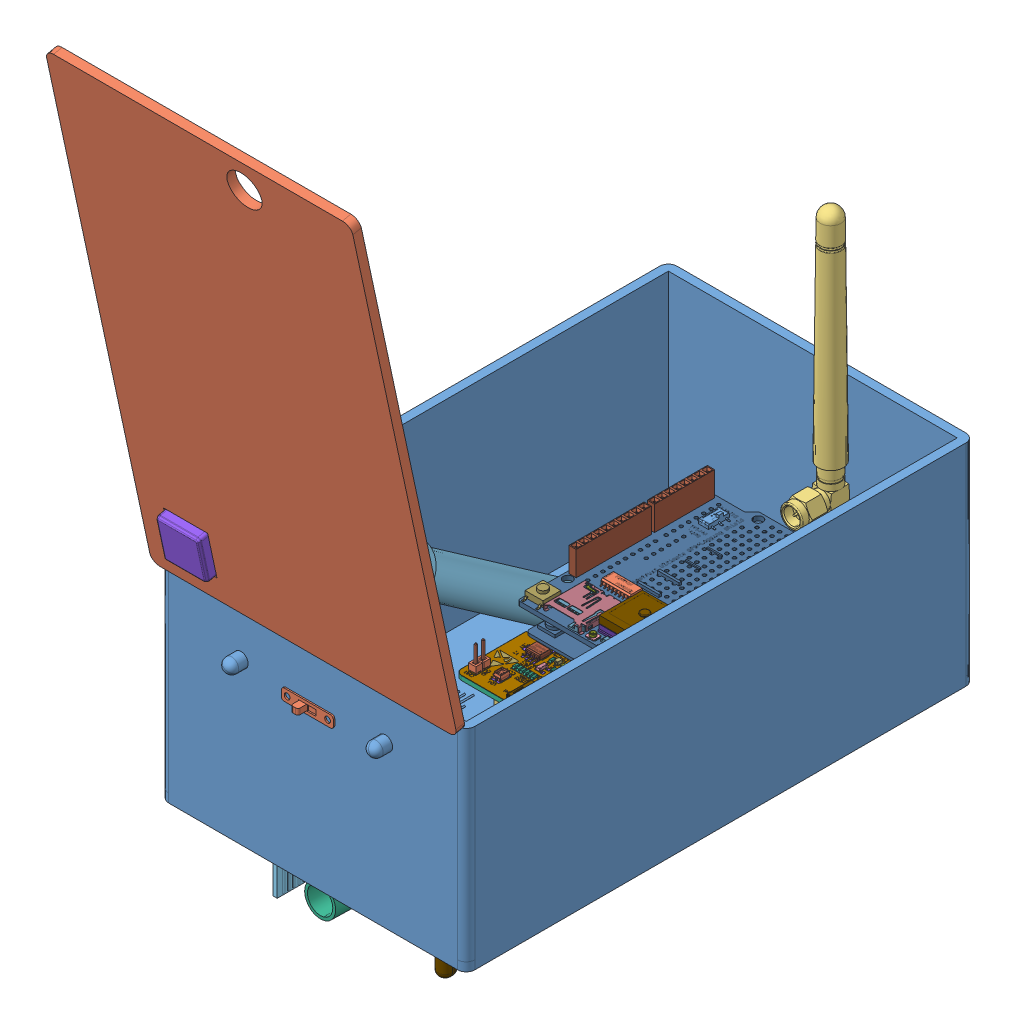
SolidWorks assembly box, configuration Défaut. Lengths in mm.
Overall size (1043.35 347.05 970.79).
170 component instances, 80 part files, 35 mates.
Components (placement in the parent):
- lower_part_box-1: lower_part_box [Défaut] at (-127.2122 -54.0126 451.3328) size (1043.35 316.3 970.79)
- upper_part_box-1: upper_part_box [Défaut] at (-127.2122 102.0269 557.8044) x (0 0.977722 0.209904) z (1 0 0) size (176 3 106)
- Batterie nel portabatterie-1: Batterie nel portabatterie [Default] at (-130.8735 -47.9133 432.4312) x (1 0 0) z (0 1 0) size (59.56 63.27 19.72)
  - User Library-R6_AA_UM3-1_5V_holder4AA-2: User Library-R6_AA_UM3-1_5V_holder4AA [4AA] at (18.4086 0.1871 -6.0993) size (59.56 61.47 15.11)
  - Batteria ricaricabile stilo-1: Batteria ricaricabile stilo [Default] at (-5.4514 -22.5579 1.9017) x (0 0 1) z (1 0 0) size (13.97 13.97 50.04)
  - Batteria ricaricabile stilo-3: Batteria ricaricabile stilo [Default] at (-5.4514 7.5731 1.9017) x (0 0 1) z (1 0 0) size (13.97 13.97 50.04)
  - Batteria ricaricabile stilo-4: Batteria ricaricabile stilo [Default] at (42.2686 -7.2677 1.9017) x (0 0.660431 0.750887) z (-1 0 0) size (13.97 13.97 50.04)
  - Batteria ricaricabile stilo-5: Batteria ricaricabile stilo [Default] at (42.2686 22.8633 1.9017) x (0 0.660431 0.750887) z (-1 0 0) size (13.97 13.97 50.04)
- ph_sonda v1.step-1: ph_sonda v1.step [Défaut] at (-166.4758 -79.6585 378.5757) x (0.97654 -0.176393 0.123512) z (0 0.573576 0.819152) size (16.6 16.6 161)
- NUCLEO-F411RE.STEP-1: NUCLEO-F411RE.STEP [Défaut] at (-121.1022 -38.1146 390.069) x (-1 0 0) z (0 1 0) size (70 83.97 20.27)
  - NUCLEO-F411RE_PCB_Varsay_lan.STEP-1: NUCLEO-F411RE_PCB_Varsay_lan.STEP [Défaut] at origin size (70 82.5 1.5)
  - NUCLEO-F411RE_PCB_HOLEs_Varsay_lan.STEP-1: NUCLEO-F411RE_PCB_HOLEs_Varsay_lan.STEP [Défaut] at origin size (65.28 79.87 1.57)
  - NUCLEO-F411RE_PCB_TOP_Pads_Varsay_lan.STEP-1: NUCLEO-F411RE_PCB_TOP_Pads_Varsay_lan.STEP [Défaut] at origin size (59.94 77.1 0.04)
  - NUCLEO-F411RE_PCB_TOP_Solder_Varsay_lan.STEP-1: NUCLEO-F411RE_PCB_TOP_Solder_Varsay_lan.STEP [Défaut] at origin size (69.8 82.3 0.05)
  - NUCLEO-F411RE_PCB_BOTTOM_Pads_Varsay_lan.STEP-1: NUCLEO-F411RE_PCB_BOTTOM_Pads_Varsay_lan.STEP [Défaut] at origin size (31.1 70.87 0.04)
  - NUCLEO-F411RE_PCB_BOTTOM_Solder_Varsay_lan.STEP-1: NUCLEO-F411RE_PCB_BOTTOM_Solder_Varsay_lan.STEP [Défaut] at origin size (69.8 82.3 0.04)
  - NUCLEO-F411RE_PCB_TOP_Overlay_Varsay_lan.STEP-1: NUCLEO-F411RE_PCB_TOP_Overlay_Varsay_lan.STEP [Défaut] at origin size (68.09 77.67 0)
  - NUCLEO-F411RE_PCB_TOP_Designators_Varsay_lan.STEP-1: NUCLEO-F411RE_PCB_TOP_Designators_Varsay_lan.STEP [Défaut] at origin size (66.29 79.64 0)
  - NUCLEO-F411RE_PCB_BOTTOM_Overlay_Varsay_lan.STEP-1: NUCLEO-F411RE_PCB_BOTTOM_Overlay_Varsay_lan.STEP [Défaut] at origin size (40.11 80.77 0)
  - SAMTEC_SSQ-106-01-G-S_for_NUCLEO_Varsay_lan.STEP-1: SAMTEC_SSQ-106-01-G-S_for_NUCLEO_Varsay_lan.STEP [Défaut] at (-33.02 8.89 0.785) x (0 1 0) z (1 0 0) size (15.75 11.15 2.41)
  - SAMTEC_SSQ-108-01-G-S_for_NUCLEO_Varsay_lan.STEP-1: SAMTEC_SSQ-108-01-G-S_for_NUCLEO_Varsay_lan.STEP [Défaut] at (-33.02 29.21 0.785) x (0 1 0) z (1 0 0) size (20.83 11.15 2.41)
  - SAMTEC_SSQ-108-01-G-S_for_NUCLEO_Varsay_lan.STEP-2: SAMTEC_SSQ-108-01-G-S_for_NUCLEO_Varsay_lan.STEP [Défaut] at (15.24 11.43 0.785) x (0 1 0) z (1 0 0) size (20.83 11.15 2.41)
  - SAMTEC_SSQ-110-01-G-S_for_NUCLEO_Varsay_lan.STEP-1: SAMTEC_SSQ-110-01-G-S_for_NUCLEO_Varsay_lan.STEP [Défaut] at (15.24 35.814 0.785) x (0 1 0) z (1 0 0) size (25.91 11.15 2.41)
  - MOLEX_0678038020_for_NUCLEO.STEP-1: MOLEX_0678038020_for_NUCLEO.STEP [Défaut] at (3.1721 75.2975 0.785) x (-1 0 0) z (0 1 0) size (9.9 4.95 9)
  - SAMTEC_TSW-119-07-T-D_for_NUCLEO_Varsay_lan.STEP-1: SAMTEC_TSW-119-07-T-D_for_NUCLEO_Varsay_lan.STEP [Défaut] at (-39.37 25.4 0.785) x (0 -1 0) z (-1 0 0) size (48.26 17.95 5.08)
  - SAMTEC_TSW-119-07-T-D_for_NUCLEO_Varsay_lan.STEP-2: SAMTEC_TSW-119-07-T-D_for_NUCLEO_Varsay_lan.STEP [Défaut] at (21.59 25.4 0.785) x (0 -1 0) z (-1 0 0) size (48.26 17.95 5.08)
  - SAMTEC_TSW-102-07-T-S_for_NUCLEO_Varsay_lan.STEP-1: SAMTEC_TSW-102-07-T-S_for_NUCLEO_Varsay_lan.STEP [Défaut] at (-40.64 74.93 0.785) x (0 1 0) z (1 0 0) size (5.08 10.92 2.54)
  - SAMTEC_TSW-102-07-T-S_for_NUCLEO_Varsay_lan.STEP-2: SAMTEC_TSW-102-07-T-S_for_NUCLEO_Varsay_lan.STEP [Défaut] at (-31.75 59.055 0.785) x (0 -1 0) z (-1 0 0) size (5.08 10.92 2.54)
  - SAMTEC_TSW-102-07-T-S_for_NUCLEO_Varsay_lan.STEP-3: SAMTEC_TSW-102-07-T-S_for_NUCLEO_Varsay_lan.STEP [Défaut] at (-9.525 77.47 0.785) x (1 0 0) z (0 -1 0) size (5.08 10.92 2.54)
  - SAMTEC_TSW-102-07-T-S_for_NUCLEO_Varsay_lan.STEP-4: SAMTEC_TSW-102-07-T-S_for_NUCLEO_Varsay_lan.STEP [Défaut] at (-9.525 38.735 0.785) x (1 0 0) z (0 -1 0) size (5.08 10.92 2.54)
  - SAMTEC_TSW-102-07-T-S_for_NUCLEO_Varsay_lan.STEP-5: SAMTEC_TSW-102-07-T-S_for_NUCLEO_Varsay_lan.STEP [Défaut] at (22.86 74.93 0.785) x (0 -1 0) z (-1 0 0) size (5.08 10.92 2.54)
  - SAMTEC_TSW-103-07-T-S_for_NUCLEO_Varsay_lan.STEP-1: SAMTEC_TSW-103-07-T-S_for_NUCLEO_Varsay_lan.STEP [Défaut] at (1.905 45.085 0.785) x (1 0 0) z (0 -1 0) size (7.62 10.92 2.54)
  - SAMTEC_TSW-104-07-T-S_for_NUCLEO_Varsay_lan.STEP-1: SAMTEC_TSW-104-07-T-S_for_NUCLEO_Varsay_lan.STEP [Défaut] at (-21.59 73.66 0.785) x (0 1 0) z (1 0 0) size (10.16 10.92 2.54)
  - SAMTEC_TSW-106-07-T-S_for_NUCLEO_Varsay_lan.STEP-1: SAMTEC_TSW-106-07-T-S_for_NUCLEO_Varsay_lan.STEP [Défaut] at (-35.56 64.77 0.785) x (0 1 0) z (1 0 0) size (15.24 10.92 2.54)
  - MOLEX_90059-0007.STEP-1: MOLEX_90059-0007.STEP [Défaut] at (-21.59 76.2 5.75) x (0 1 0) z (1 0 0) size (5.1 4.85 2.54)
  - MOLEX_90059-0007.STEP-2: MOLEX_90059-0007.STEP [Défaut] at (-21.59 71.12 5.75) x (0 -1 0) z (-1 0 0) size (5.1 4.85 2.54)
  - ST_STM32F411RET6_Varsay_lan.STEP-1: ST_STM32F411RET6_Varsay_lan.STEP [Défaut] at (-11.4265 21.5935 0.785) x (-1 0 0) z (0 0 -1) size (12 12 1.6)
  - ST_STM32F103CBT6_Varsay_lan.STEP-1: ST_STM32F103CBT6_Varsay_lan.STEP [Défaut] at (-8.89 64.77 0.785) x (1 0 0) z (0 -1 0) size (9 1.6 9)
  - ESWITCH_TL3301SPF160QGBLK_Varsay_lan.STEP-1: ESWITCH_TL3301SPF160QGBLK_Varsay_lan.STEP [Défaut] at (-0.635 50.8 0.785) x (0 -1 0) z (-1 0 0) size (6 10.7 10)
  - ESWITCH_TL3301SPF160QGBLU_Varsay_lan.STEP-1: ESWITCH_TL3301SPF160QGBLU_Varsay_lan.STEP [Défaut] at (-17.145 50.8 0.785) x (0 1 0) z (1 0 0) size (6 10.7 10)
  - ST_STS7PF30L_Varsay_lan.STEP-1: ST_STS7PF30L_Varsay_lan.STEP [Défaut] at (17.145 60.325 0.785) x (-1 0 0) z (0 1 0) size (4.9 1.75 6)
  - ABRACON_ABL-8.000MHZ-B2_Varsay_lan.STEP-1: ABRACON_ABL-8.000MHZ-B2_Varsay_lan.STEP [Défaut] at (-18.41 63.4908 0.785) x (0 -1 0) z (-1 0 0) size (11.5 5.57 5)
  - ST_LD1117S50TR_Varsay_lan.STEP-1: ST_LD1117S50TR_Varsay_lan.STEP [Défaut] at (-14.6685 43.18 0.785) x (0 -1 0) z (-1 0 0) size (6.5 1.9 7)
  - ST_LD39050PU33R_Varsay_lan.STEP-1: ST_LD39050PU33R_Varsay_lan.STEP [Défaut] at (1.905 40.64 0.785) x (0 1 0) z (1 0 0) size (3 1 3)
  - ST_LD3985M33R_Varsay_lan.STEP-1: ST_LD3985M33R_Varsay_lan.STEP [Défaut] at (7.62 63.5 0.785) x (1 0 0) z (0 -1 0) size (2.95 1.45 2.8)
  - KEMET_T491B106K025AT_Varsay_lan.STEP-1: KEMET_T491B106K025AT_Varsay_lan.STEP [Défaut] at (-22.86 41.275 0.785) x (0 -1 0) z (-1 0 0) size (2.8 1.9 3.5)
  - ST_STPS2L30A_Varsay_lan.STEP-1: ST_STPS2L30A_Varsay_lan.STEP [Défaut] at (-22.86 45.085 0.785) x (0 1 0) z (1 0 0) size (2.58 2.3 5.07)
  - KEMET_T491A106K006AT7280_Varsay_lan.STEP-1: KEMET_T491A106K006AT7280_Varsay_lan.STEP [Défaut] at (-8.255 43.053 0.785) x (1 0 0) z (0 -1 0) size (1.6 1.6 3.2)
  - ABRACON_ABS25-32.768KHZ-6-T_Varsay_lan.STEP-1: ABRACON_ABS25-32.768KHZ-6-T_Varsay_lan.STEP [Défaut] at (-23.495 6.35 0.785) x (1 0 0) z (0 -1 0) size (8 2.66 4)
  - LUMEX_SML-LX2835IGC-TR.STEP-1: LUMEX_SML-LX2835IGC-TR.STEP [Défaut] at (16.51 73.66 0.785) x (1 0 0) z (0 -1 0) size (2.7 1.8 3.5)
  - MOLEX_90059-0007.STEP-3: MOLEX_90059-0007.STEP [Défaut] at (3.175 45.085 5.75) x (-1 0 0) z (0 1 0) size (5.1 4.85 2.54)
  - ST_BAT60JFILM_Varsay_lan.STEP-1: ST_BAT60JFILM_Varsay_lan.STEP [Défaut] at (-31.115 71.12 0.785) x (0 -1 0) z (-1 0 0) size (1.28 1.17 2.5)
  - ST_BAT60JFILM_Varsay_lan.STEP-2: ST_BAT60JFILM_Varsay_lan.STEP [Défaut] at (7.62 69.85 0.785) x (0 -1 0) z (-1 0 0) size (1.28 1.17 2.5)
  - NXP_BC847B,215.STEP-1: NXP_BC847B,215.STEP [Défaut] at (12.065 64.135 0.785) x (0 -1 0) z (-1 0 0) size (2.9 1.1 2.43)
  - ST_BAT60JFILM_Varsay_lan.STEP-3: ST_BAT60JFILM_Varsay_lan.STEP [Défaut] at (10.795 59.69 0.785) x (1 0 0) z (0 -1 0) size (1.28 1.17 2.5)
  - YAGEO_CC0805KKX7R7BB225.STEP-1: YAGEO_CC0805KKX7R7BB225.STEP [Défaut] at (0.127 23.495 0.785) x (0 -1 0) z (-1 0 0) size (1.58 1.29 4.06)
  - YAGEO_RC0603JR-070RL.STEP-1: YAGEO_RC0603JR-070RL.STEP [Défaut] at (17.145 67.945 0.785) x (1 0 0) z (0 -1 0) size (0.8 0.55 2.16)
  - YAGEO_RC0603JR-070RL.STEP-2: YAGEO_RC0603JR-070RL.STEP [Défaut] at (15.875 67.945 0.785) x (1 0 0) z (0 -1 0) size (0.8 0.55 2.16)
  - YAGEO_RC0603JR-070RL.STEP-3: YAGEO_RC0603JR-070RL.STEP [Défaut] at (14.605 67.945 0.785) x (1 0 0) z (0 -1 0) size (0.8 0.55 2.16)
  - YAGEO_RC0603JR-070RL.STEP-4: YAGEO_RC0603JR-070RL.STEP [Défaut] at (13.335 67.945 0.785) x (1 0 0) z (0 -1 0) size (0.8 0.55 2.16)
  - YAGEO_RC0603JR-070RL.STEP-5: YAGEO_RC0603JR-070RL.STEP [Défaut] at (12.065 67.945 0.785) x (1 0 0) z (0 -1 0) size (0.8 0.55 2.16)
  - YAGEO_RC0603JR-070RL.STEP-6: YAGEO_RC0603JR-070RL.STEP [Défaut] at (10.795 67.945 0.785) x (1 0 0) z (0 -1 0) size (0.8 0.55 2.16)
  - YAGEO_RC0603JR-070RL.STEP-7: YAGEO_RC0603JR-070RL.STEP [Défaut] at (12.7 59.7535 0.785) x (1 0 0) z (0 -1 0) size (0.8 0.55 2.16)
  - YAGEO_RC0603JR-070RL.STEP-8: YAGEO_RC0603JR-070RL.STEP [Défaut] at (4.445 67.945 0.785) x (1 0 0) z (0 -1 0) size (0.8 0.55 2.16)
  - YAGEO_RC0603JR-070RL.STEP-9: YAGEO_RC0603JR-070RL.STEP [Défaut] at (3.175 67.945 0.785) x (1 0 0) z (0 -1 0) size (0.8 0.55 2.16)
  - YAGEO_RC0603JR-070RL.STEP-10: YAGEO_RC0603JR-070RL.STEP [Défaut] at (1.905 67.945 0.785) x (1 0 0) z (0 -1 0) size (0.8 0.55 2.16)
  - YAGEO_RC0603JR-070RL.STEP-11: YAGEO_RC0603JR-070RL.STEP [Défaut] at (0 67.945 0.785) x (1 0 0) z (0 -1 0) size (0.8 0.55 2.16)
  - YAGEO_RC0603JR-070RL.STEP-12: YAGEO_RC0603JR-070RL.STEP [Défaut] at (-6.985 73.025 0.785) x (1 0 0) z (0 -1 0) size (0.8 0.55 2.16)
  - YAGEO_RC0603JR-070RL.STEP-13: YAGEO_RC0603JR-070RL.STEP [Défaut] at (-8.255 73.025 0.785) x (1 0 0) z (0 -1 0) size (0.8 0.55 2.16)
  - YAGEO_RC0603JR-070RL.STEP-14: YAGEO_RC0603JR-070RL.STEP [Défaut] at (-9.525 73.025 0.785) x (1 0 0) z (0 -1 0) size (0.8 0.55 2.16)
  - YAGEO_RC0603JR-070RL.STEP-15: YAGEO_RC0603JR-070RL.STEP [Défaut] at (-14.605 73.025 0.785) x (1 0 0) z (0 -1 0) size (0.8 0.55 2.16)
  - YAGEO_RC0603JR-070RL.STEP-16: YAGEO_RC0603JR-070RL.STEP [Défaut] at (-31.115 73.025 0.785) x (0 -1 0) z (-1 0 0) size (0.8 0.55 2.16)
  - YAGEO_RC0603JR-070RL.STEP-17: YAGEO_RC0603JR-070RL.STEP [Défaut] at (-31.115 69.215 0.785) x (0 -1 0) z (-1 0 0) size (0.8 0.55 2.16)
  - YAGEO_RC0603JR-070RL.STEP-18: YAGEO_RC0603JR-070RL.STEP [Défaut] at (-31.115 67.31 0.785) x (0 -1 0) z (-1 0 0) size (0.8 0.55 2.16)
  - YAGEO_RC0603JR-070RL.STEP-19: YAGEO_RC0603JR-070RL.STEP [Défaut] at (-31.115 65.405 0.785) x (0 -1 0) z (-1 0 0) size (0.8 0.55 2.16)
  - YAGEO_RC0603JR-070RL.STEP-20: YAGEO_RC0603JR-070RL.STEP [Défaut] at (-31.115 63.5 0.785) x (0 -1 0) z (-1 0 0) size (0.8 0.55 2.16)
  - YAGEO_RC0603JR-070RL.STEP-21: YAGEO_RC0603JR-070RL.STEP [Défaut] at (-25.4 64.77 0.785) x (0 -1 0) z (-1 0 0) size (0.8 0.55 2.16)
  - YAGEO_RC0603JR-070RL.STEP-22: YAGEO_RC0603JR-070RL.STEP [Défaut] at (-25.4 63.5 0.785) x (0 -1 0) z (-1 0 0) size (0.8 0.55 2.16)
  - YAGEO_RC0603JR-070RL.STEP-23: YAGEO_RC0603JR-070RL.STEP [Défaut] at (-25.4 62.23 0.785) x (0 -1 0) z (-1 0 0) size (0.8 0.55 2.16)
  - YAGEO_RC0603JR-070RL.STEP-24: YAGEO_RC0603JR-070RL.STEP [Défaut] at (-25.4 60.96 0.785) x (0 -1 0) z (-1 0 0) size (0.8 0.55 2.16)
  - YAGEO_RC0603JR-070RL.STEP-25: YAGEO_RC0603JR-070RL.STEP [Défaut] at (-15.875 11.43 0.785) x (1 0 0) z (0 -1 0) size (0.8 0.55 2.16)
  - YAGEO_RC0603JR-070RL.STEP-26: YAGEO_RC0603JR-070RL.STEP [Défaut] at (-14.605 11.43 0.785) x (1 0 0) z (0 -1 0) size (0.8 0.55 2.16)
  - YAGEO_RC0603JR-070RL.STEP-27: YAGEO_RC0603JR-070RL.STEP [Défaut] at (-22.225 18.415 0.785) x (1 0 0) z (0 -1 0) size (0.8 0.55 2.16)
  - YAGEO_RC0603JR-070RL.STEP-28: YAGEO_RC0603JR-070RL.STEP [Défaut] at (-20.955 32.385 0.785) x (0 -1 0) z (-1 0 0) size (0.8 0.55 2.16)
  - YAGEO_RC0603JR-070RL.STEP-29: YAGEO_RC0603JR-070RL.STEP [Défaut] at (-8.89 51.435 0.785) x (0 -1 0) z (-1 0 0) size (0.8 0.55 2.16)
  - YAGEO_RC0603JR-070RL.STEP-30: YAGEO_RC0603JR-070RL.STEP [Défaut] at (-8.89 47.625 0.785) x (0 -1 0) z (-1 0 0) size (0.8 0.55 2.16)
  - YAGEO_RC0603JR-070RL.STEP-31: YAGEO_RC0603JR-070RL.STEP [Défaut] at (3.81 36.83 0.785) x (0 -1 0) z (-1 0 0) size (0.8 0.55 2.16)
  - YAGEO_RC0603JR-070RL.STEP-32: YAGEO_RC0603JR-070RL.STEP [Défaut] at (0 63.5 0.785) x (0 -1 0) z (-1 0 0) size (0.8 0.55 2.16)
  - YAGEO_RC0603JR-070RL.STEP-33: YAGEO_RC0603JR-070RL.STEP [Défaut] at (0 62.23 0.785) x (0 -1 0) z (-1 0 0) size (0.8 0.55 2.16)
  - YAGEO_CC0603KRX7R7BB104.STEP-1: YAGEO_CC0603KRX7R7BB104.STEP [Défaut] at (-11.43 73.025 0.785) x (1 0 0) z (0 -1 0) size (0.8 0.8 2.16)
  - YAGEO_CC0603KRX7R7BB104.STEP-2: YAGEO_CC0603KRX7R7BB104.STEP [Défaut] at (-1.905 67.945 0.785) x (1 0 0) z (0 -1 0) size (0.8 0.8 2.16)
  - YAGEO_CC0603KRX7R7BB104.STEP-3: YAGEO_CC0603KRX7R7BB104.STEP [Défaut] at (5.08 62.865 0.785) x (1 0 0) z (0 -1 0) size (0.8 0.8 2.16)
  - YAGEO_CC0603KRX7R7BB104.STEP-4: YAGEO_CC0603KRX7R7BB104.STEP [Défaut] at (6.985 59.69 0.785) x (1 0 0) z (0 -1 0) size (0.8 0.8 2.16)
  - YAGEO_CC0603KRX7R7BB104.STEP-5: YAGEO_CC0603KRX7R7BB104.STEP [Défaut] at (8.89 59.69 0.785) x (1 0 0) z (0 -1 0) size (0.8 0.8 2.16)
  - YAGEO_CC0603KRX7R7BB104.STEP-6: YAGEO_CC0603KRX7R7BB104.STEP [Défaut] at (-21.59 62.23 0.785) x (1 0 0) z (0 -1 0) size (0.8 0.8 2.16)
  - YAGEO_CC0603KRX7R7BB104.STEP-7: YAGEO_CC0603KRX7R7BB104.STEP [Défaut] at (-21.59 64.77 0.785) x (1 0 0) z (0 -1 0) size (0.8 0.8 2.16)
  - YAGEO_CC0603KRX7R7BB104.STEP-8: YAGEO_CC0603KRX7R7BB104.STEP [Défaut] at (-15.24 63.5 0.785) x (1 0 0) z (0 -1 0) size (0.8 0.8 2.16)
  - YAGEO_CC0603KRX7R7BB104.STEP-9: YAGEO_CC0603KRX7R7BB104.STEP [Défaut] at (-6.35 58.42 0.785) x (0 -1 0) z (-1 0 0) size (0.8 0.8 2.16)
  - YAGEO_CC0603KRX7R7BB104.STEP-10: YAGEO_CC0603KRX7R7BB104.STEP [Défaut] at (-8.89 53.34 0.785) x (0 -1 0) z (-1 0 0) size (0.8 0.8 2.16)
  - YAGEO_CC0603KRX7R7BB104.STEP-11: YAGEO_CC0603KRX7R7BB104.STEP [Défaut] at (-8.89 49.53 0.785) x (0 -1 0) z (-1 0 0) size (0.8 0.8 2.16)
  - YAGEO_CC0603KRX7R7BB104.STEP-12: YAGEO_CC0603KRX7R7BB104.STEP [Défaut] at (-2.54 40.64 0.785) x (1 0 0) z (0 -1 0) size (0.8 0.8 2.16)
  - YAGEO_CC0603KRX7R7BB104.STEP-13: YAGEO_CC0603KRX7R7BB104.STEP [Défaut] at (-1.27 40.64 0.785) x (1 0 0) z (0 -1 0) size (0.8 0.8 2.16)
  - YAGEO_CC0603KRX7R7BB104.STEP-14: YAGEO_CC0603KRX7R7BB104.STEP [Défaut] at (5.08 40.64 0.785) x (1 0 0) z (0 -1 0) size (0.8 0.8 2.16)
  - YAGEO_CC0603KRX7R7BB104.STEP-15: YAGEO_CC0603KRX7R7BB104.STEP [Défaut] at (6.35 40.64 0.785) x (1 0 0) z (0 -1 0) size (0.8 0.8 2.16)
  - YAGEO_CC0603KRX7R7BB104.STEP-16: YAGEO_CC0603KRX7R7BB104.STEP [Défaut] at (-0.6033 27.94 0.785) x (0 -1 0) z (-1 0 0) size (0.8 0.8 2.16)
  - YAGEO_CC0603KRX7R7BB104.STEP-17: YAGEO_CC0603KRX7R7BB104.STEP [Défaut] at (-17.145 32.385 0.785) x (1 0 0) z (0 -1 0) size (0.8 0.8 2.16)
  - YAGEO_CC0603KRX7R7BB104.STEP-18: YAGEO_CC0603KRX7R7BB104.STEP [Défaut] at (-20.32 18.415 0.785) x (1 0 0) z (0 -1 0) size (0.8 0.8 2.16)
  - YAGEO_CC0603KRX7R7BB104.STEP-19: YAGEO_CC0603KRX7R7BB104.STEP [Défaut] at (-17.145 11.43 0.785) x (1 0 0) z (0 -1 0) size (0.8 0.8 2.16)
  - YAGEO_CC0603KRX7R7BB104.STEP-20: YAGEO_CC0603KRX7R7BB104.STEP [Défaut] at (0 17.78 0.785) x (0 -1 0) z (-1 0 0) size (0.8 0.8 2.16)
  - YAGEO_CC0603KRX7R7BB104.STEP-21: YAGEO_CC0603KRX7R7BB104.STEP [Défaut] at (-8.636 12.192 0.785) x (0 -1 0) z (-1 0 0) size (0.8 0.8 2.16)
  - YAGEO_CC0603KRX7R7BB104.STEP-22: YAGEO_CC0603KRX7R7BB104.STEP [Défaut] at (-19.685 2.794 0.785) x (0 -1 0) z (-1 0 0) size (0.8 0.8 2.16)
  - YAGEO_CC0603KRX7R7BB104.STEP-23: YAGEO_CC0603KRX7R7BB104.STEP [Défaut] at (-19.685 10.795 0.785) x (0 -1 0) z (-1 0 0) size (0.8 0.8 2.16)
  - LUMEX_SML-LX0603SRW-TR.STEP-1: LUMEX_SML-LX0603SRW-TR.STEP [Défaut] at (0.635 36.83 0.785) x (1 0 0) z (0 -1 0) size (2.17 0.59 0.81)
  - LUMEX_SML-LX0603GW-TR.STEP-1: LUMEX_SML-LX0603GW-TR.STEP [Défaut] at (-21.1455 35.5597 0.785) x (1 0 0) z (0 -1 0) size (2.17 0.59 0.81)
- arduino motor shield-1: arduino motor shield [Predeterminado] at (-112.2382 -29.8206 420.2097) x (0 0 1) z (-1 0 0) size (68 21.5 53)
- Adafruit Ultimate GPS Logger Shield.stp-1: Adafruit Ultimate GPS Logger Shield.stp [Défaut] at (-181.6007 -21.0346 419.277) x (0 0 -1) z (1 0 0) size (68.2 11.7 53.05)
  - microSD_Connector.stp-1: microSD_Connector.stp [Défaut] at (-28.4341 1.764 56.1048) x (0 0 -1) z (1 0 0) size (14.11 1.91 15.46)
    - microSD_Pin_11.35.stp-1: microSD_Pin_11.35.stp [Défaut] at (1.325 0 -2) x (0 0 1) z (-1 0 0) size (7.35 1.15 0.63)
    - microSD_Pin_11.15.stp-1: microSD_Pin_11.15.stp [Défaut] at (2.425 0 -2) x (0 0 1) z (-1 0 0) size (7.35 1.15 0.62)
    - microSD_Pin_11.15.stp-2: microSD_Pin_11.15.stp [Défaut] at (-1.975 0 -2) x (0 0 1) z (-1 0 0) size (7.35 1.15 0.62)
    - microSD_Cover.stp-1: microSD_Cover.stp [Défaut] at (0 1.7 0) x (1 0 0) z (0 0 -1) size (13.96 1.91 15.21)
    - microSD_Pin_11.35.stp-2: microSD_Pin_11.35.stp [Défaut] at (3.525 0 -2) x (0 0 1) z (-1 0 0) size (7.35 1.15 0.63)
    - microSD_Body.stp-1: microSD_Body.stp [Défaut] at origin size (14.1 1.85 15.2)
    - microSD_Pin_10.75.stp-1: microSD_Pin_10.75.stp [Défaut] at (-0.875 0 -2) x (0 0 1) z (-1 0 0) size (7.25 1.15 0.62)
    - microSD_Pin_11.15.stp-3: microSD_Pin_11.15.stp [Défaut] at (4.625 0 -2) x (0 0 1) z (-1 0 0) size (7.35 1.15 0.62)
    - microSD_Card_Detect.stp-1: microSD_Card_Detect.stp [Défaut] at (4.99 -0.05 7.4) size (4.45 1.91 2.06)
    - microSD_Pin_11.15.stp-4: microSD_Pin_11.15.stp [Défaut] at (5.725 0 -2) x (0 0 1) z (-1 0 0) size (7.35 1.15 0.62)
    - microSD_Pin_11.15.stp-5: microSD_Pin_11.15.stp [Défaut] at (0.225 0 -2) x (0 0 1) z (-1 0 0) size (7.35 1.15 0.62)
  - MODULO GPS_SMD.stp-1: MODULO GPS_SMD.stp [Défaut] at (-24.1111 1.764 72.4983) x (1 0 0) z (0 1 0) size (16 16 5.2)
    - FGPMMOPA6H_BASE.stp-1: FGPMMOPA6H_BASE.stp [Défaut] at origin size (16 16 2)
    - FGPMMOPA6H_TOP.stp-1: FGPMMOPA6H_TOP.stp [Défaut] at origin size (15 15 3)
  - SLIDE SWITCH DPDT_SMD.stp-1: SLIDE SWITCH DPDT_SMD.stp [Défaut] at (17.6649 1.764 51.831) x (0 0 1) z (0 1 0) size (6 7.2 3)
    - SLIDE SWITCH.stp-1: SLIDE SWITCH.stp [Défaut] at origin size (6 7.2 3)
  - 74HC4049_74HC4050.stp-1: 74HC4049_74HC4050.stp [Défaut] at (-15.3745 1.9423 51.4831) x (-1 0 0) z (0 1 0) size (5.85 10 1.8)
    - BODY.stp-1: BODY.stp [Défaut] at origin size (5.85 10 1.8)
  - SW3dPS-UFL-R-SMD.stp-1: SW3dPS-UFL-R-SMD.stp [Défaut] at (-34.458 1.764 65.7075) x (0 0 1) z (0 1 0) size (3.4 3.1 1.25)
    - SW3dPS-UFL-R-SMD_Part_578.stp-1: SW3dPS-UFL-R-SMD_Part_578.stp [Défaut] at origin size (0.6 0.5 0.1)
    - SW3dPS-UFL-R-SMD_Part_525.stp-1: SW3dPS-UFL-R-SMD_Part_525.stp [Défaut] at origin size (3 2.6 0.35)
    - SW3dPS-UFL-R-SMD_Part_555.stp-1: SW3dPS-UFL-R-SMD_Part_555.stp [Défaut] at origin size (0.6 0.5 0.1)
    - SW3dPS-UFL-R-SMD_Part_562.stp-1: SW3dPS-UFL-R-SMD_Part_562.stp [Défaut] at origin size (0.4 1.8 0.1)
    - SW3dPS-UFL-R-SMD_Part_739.stp-1: SW3dPS-UFL-R-SMD_Part_739.stp [Défaut] at origin size (2.01 2 0.91)
    - SW3dPS-UFL-R-SMD_Part_540.stp-1: SW3dPS-UFL-R-SMD_Part_540.stp [Défaut] at origin size (0.4 1.8 0.1)
  - MIC5225-3.3YM5.stp-1: MIC5225-3.3YM5.stp [Défaut] at (-12.2756 3.1697 88.6135) x (0 0 -1) z (0 1 0) size (3.05 3.05 1.3)
    - CHIP.stp-1: CHIP.stp [Défaut] at origin size (3.05 3.05 1.3)
  - PCB Adafruit Ultimate GPS Logger Shield.stp-1: PCB Adafruit Ultimate GPS Logger Shield.stp [Défaut] at (-36.508 0.214 94.725) size (68.2 1.56 53.05)
  - pins connection Shield.stp-1: pins connection Shield.stp [Défaut] at (-10.308 1.764 93.525) size (47.95 11.7 50.9)
  - Buton.stp-1: Buton.stp [Défaut] at (-34.4592 1.764 48.375) size (9.48 3.1 6.2)
  - SW3dPS-3002.stp-1: SW3dPS-3002.stp [Défaut] at (-26.3169 1.764 88.3628) x (-1 0 0) z (0 0 -1) size (18.44 2.78 12.04)
  - LED SMD.stp-1: LED SMD.stp [Défaut] at (-33.7112 1.764 69.9441) x (0 0 -1) z (0 1 0) size (3.21 1.61 1.15)
  - LED SMD.stp-2: LED SMD.stp [Défaut] at (-33.7112 1.764 75.4441) x (0 0 -1) z (0 1 0) size (3.21 1.61 1.15)
  - LED SMD.stp-3: LED SMD.stp [Défaut] at (-33.7112 1.764 80.9441) x (0 0 -1) z (0 1 0) size (3.21 1.61 1.15)
  - SMD RESISTOR-0805.stp-1: SMD RESISTOR-0805.stp [Défaut] at (-34.9121 2.064 84.7392) size (1.25 0.61 2)
  - SMD RESISTOR-0805.stp-2: SMD RESISTOR-0805.stp [Défaut] at (-14.0292 2.064 67.8714) size (1.25 0.61 2)
  - SMD RESISTOR-0805.stp-3: SMD RESISTOR-0805.stp [Défaut] at (-13.5461 2.064 63.138) x (0 0 -1) z (1 0 0) size (1.25 0.61 2)
  - SMD RESISTOR-0805.stp-4: SMD RESISTOR-0805.stp [Défaut] at (-17.3775 2.064 63.138) x (0 0 -1) z (1 0 0) size (1.25 0.61 2)
  - SMD CAPACITOR 0603.stp-1: SMD CAPACITOR 0603.stp [Défaut] at (-13.8958 2.164 92.2529) size (1.6 0.81 0.81)
  - SMD CAPACITOR 0603.stp-2: SMD CAPACITOR 0603.stp [Défaut] at (-13.8958 2.164 85.2529) size (1.6 0.81 0.81)
  - SMD CAPACITOR 0603.stp-3: SMD CAPACITOR 0603.stp [Défaut] at (-14.1323 2.164 79.4186) x (0 0 -1) z (1 0 0) size (1.6 0.81 0.81)
  - SMD CAPACITOR 0402.stp-1: SMD CAPACITOR 0402.stp [Défaut] at (-16.4867 2.014 83.0672) size (1.01 0.51 0.51)
- Part1.catpart-1: Part1.catpart [Défaut] at (-97.7182 -57.0126 510.5258) x (0 1 0) z (1 0 0) size (55 40 15)
- LED_RGB.stp-1: LED_RGB.stp [Défaut] at (-152.2122 -1.5126 536.3328) size (5 4.9 35.65)
- LED_RGB.stp-2: LED_RGB.stp [Défaut] at (-102.2122 -1.5126 536.3328) x (0.767252 -0.641345 0) z (0 0 1) size (5 4.9 35.65)
- Slide_Switch-1: Slide_Switch [Default] at (-128.7122 -4.0126 534.8328) x (1 0 0) z (0 -1 0) size (18 11.9 4)
- Antenna 868__F-1: Antenna 868__F [По умолчанию] at (-113.4703 -15.2706 373.885) x (-1 0 0) z (0 0 -1) size (9.24 90.6 18.05)
- Universal Qi Wireless Receiver Module-1: Universal Qi Wireless Receiver Module [Default] at (-107.7829 50.7555 545.2629) x (0 0.977722 0.209904) z (1 0 0) size (36 1.8 48)
- Capteur Pluie2 v3.step-1: Capteur Pluie2 v3.step [Défaut] at (-159.1469 -52.3896 511.0581) x (0 -1 0) z (0 0 1) size (65.03 8 20.2)
- Amphenol_TST-10-1: Amphenol_TST-10 [Default] at (-136.077 -52.1783 504.7779) x (0.999722 0 0.023582) z (0.023582 0 -0.999722) size (37.72 35 50)
  - Amphenol_TST-10-1: Amphenol_TST-10 [Default] at (9.0169 -14.1657 -6.344) size (28 33 50)
  - Amphenol_TST-10_Base-1: Amphenol_TST-10_Base [Default] at (9.0169 -15.1657 -6.344) size (37.72 14 30)
- M8Q.step-1: M8Q.step [Défaut] at (-163.4756 31.8783 541.7216) x (0 0.977722 0.209904) z (1 0 0) size (20 9.86 20)
Mates (geometry in assembly coordinates):
- Coaxiale1: concentric: cylinder of lower_part_box-1 through (-166.4758 -2.8436 488.2787) axis (0 0.573576 0.819152) radius 5.4624; cylinder of ph_sonda v1.step-1 through (-166.4758 -48.6853 422.8099) axis (0 -0.573576 -0.819152) radius 6.5
- Coïncidente4: coincident: plane of lower_part_box-1 through (-77.2122 15.9874 366.3328) normal (-1 0 0); plane of NUCLEO-F411RE.STEP-1/NUCLEO-F411RE_PCB_Varsay_lan.STEP-1 through (-77.2122 -37.3656 391.569) normal (1 0 0)
- Coïncidente15: coincident: plane of NUCLEO-F411RE.STEP-1/SAMTEC_SSQ-106-01-G-S_for_NUCLEO_Varsay_lan.STEP-1 through (-86.8757 -28.8206 391.085) normal (0 0 -1); plane of arduino motor shield-1 through (-89.3757 -28.8206 391.085) normal (0 0 -1)
- Coïncidente16: coincident: line of NUCLEO-F411RE.STEP-1/SAMTEC_SSQ-108-01-G-S_for_NUCLEO_Varsay_lan.STEP-1 through (-86.8757 -28.8206 429.693) axis (0 0 -1); line of arduino motor shield-1 through (-86.8757 -28.8206 424.285) axis (0 0 -1)
- Parallèle6: parallel: plane of NUCLEO-F411RE.STEP-1/SAMTEC_SSQ-110-01-G-S_for_NUCLEO_Varsay_lan.STEP-1 through (-137.5487 -28.8206 412.929) normal (-1 0 0); plane of arduino motor shield-1 through (-137.3629 -28.8206 438.085) normal (-1 0 0)
- Parallèle8: parallel: plane of arduino motor shield-1 through (-89.3757 -20.8206 403.785) normal (0 1 0); plane of Adafruit Ultimate GPS Logger Shield.stp-1/PCB Adafruit Ultimate GPS Logger Shield.stp-1 through (-86.8757 -20.8206 455.785) normal (0 -1 0)
- Coïncidente22: coincident: line of arduino motor shield-1 through (-86.8757 -20.8206 424.285) axis (0 0 -1); line of Adafruit Ultimate GPS Logger Shield.stp-1/PCB Adafruit Ultimate GPS Logger Shield.stp-1 through (-86.8757 -20.8206 455.085) axis (0 0 -1)
- Coïncidente24: coincident: plane of arduino motor shield-1 through (-137.3629 -28.8206 391.085) normal (0 0 -1); plane of Adafruit Ultimate GPS Logger Shield.stp-1/pins connection Shield.stp-1 through (-136.4757 -10.7706 391.085) normal (0 0 -1)
- Coïncidente25: coincident: plane of lower_part_box-1 through (-127.2122 -57.0126 451.3328) normal (0 -1 0); plane of Part1.catpart-1 through (-97.7182 -57.0126 510.5258) normal (0 1 0)
- Verrouiller1: lock: unknown of lower_part_box-1; unknown of Part1.catpart-1
- Coïncidente30: coincident: plane of Batterie nel portabatterie-1/User Library-R6_AA_UM3-1_5V_holder4AA-2 through (-140.9129 -38.8996 462.9781) normal (0 1 0); plane of NUCLEO-F411RE.STEP-1/NUCLEO-F411RE_PCB_BOTTOM_Solder_Varsay_lan.STEP-1 through (-131.2122 -38.8996 445.069) normal (0 -1 0)
- Verrouiller2: lock: unknown of ?; unknown of ?
- Coïncidente32: coincident: plane of lower_part_box-1 through (-127.2122 -54.0126 451.3328) normal (0 1 0); plane of Batterie nel portabatterie-1/User Library-R6_AA_UM3-1_5V_holder4AA-2 through (-140.9129 -54.0126 462.9781) normal (0 -1 0)
- Coaxiale2: concentric: cylinder of lower_part_box-1 through (-152.2122 -1.5126 539.3328) axis (0 0 -1) radius 2.5; cylinder of LED_RGB.stp-1 through (-152.2122 -1.5126 541.1578) axis (0 0 -1) radius 2.45
- Coïncidente33: coincident: circle of lower_part_box-1; plane of LED_RGB.stp-1 through (-149.7622 -1.5126 536.3328) normal (0 0 -1)
- Coaxiale4: concentric: cylinder of lower_part_box-1 through (-102.2122 -1.5126 539.3328) axis (0 0 -1) radius 2.5; cylinder of LED_RGB.stp-2 through (-102.2122 -1.5126 541.1578) axis (0 0 -1) radius 2.45
- Coïncidente34: coincident: plane of lower_part_box-1 through (-77.2122 15.9874 536.3328) normal (0 0 -1); plane of LED_RGB.stp-2 through (-100.3324 -3.0839 536.3328) normal (0 0 -1)
- Coïncidente35: coincident: plane of lower_part_box-1 through (-120.7122 -6.0126 539.3328) normal (0 1 0); plane of Slide_Switch-1 through (-133.7122 -6.0126 539.8328) normal (0 -1 0)
- Coïncidente36: coincident: plane of lower_part_box-1 through (-133.7122 -6.0126 539.3328) normal (1 0 0); plane of Slide_Switch-1 through (-133.7122 -2.0126 539.8328) normal (-1 0 0)
- Coïncidente37: coincident: line of Slide_Switch-1 through (-136.7122 -6.0126 539.3328) axis (1 0 0); line of lower_part_box-1 through (-123.7122 -6.0126 539.3328) axis (-1 0 0)
- Coïncidente38: coincident: plane of Adafruit Ultimate GPS Logger Shield.stp-1/PCB Adafruit Ultimate GPS Logger Shield.stp-1 through (-86.8757 -19.2706 455.785) normal (0 1 0); plane of Antenna 868__F-1 through (-115.7797 -19.2706 385.135) normal (0 -1 0)
- Coïncidente39: coincident: plane of Adafruit Ultimate GPS Logger Shield.stp-1/PCB Adafruit Ultimate GPS Logger Shield.stp-1 through (-91.6757 -19.2706 387.585) normal (0 0 -1); plane of Antenna 868__F-1 through (-113.4703 -15.2706 387.585) normal (0 0 1)
- Coïncidente40: coincident: plane of upper_part_box-1 through (-127.2122 102.0269 557.8044) normal (0 0.209904 -0.977722); plane of Universal Qi Wireless Receiver Module-1 through (-105.4602 44.8241 545.5237) normal (0 -0.209904 0.977722)
- Coïncidente46: coincident: line of lower_part_box-1 through (-177.2122 15.9874 539.3328) axis (1 0 0); line of upper_part_box-1 through (-177.2122 15.9874 539.3328) axis (1 0 0)
- Coïncidente47: coincident: plane of lower_part_box-1 through (-74.2122 15.9874 363.3328) normal (1 0 0); plane of upper_part_box-1 through (-74.2122 15.3577 542.266) normal (1 0 0)
- Verrouiller4: lock: unknown of upper_part_box-1; unknown of Universal Qi Wireless Receiver Module-1
- Coïncidente50: coincident: plane of lower_part_box-1 through (-159.1469 -57.0126 501.3328) normal (1 0 0); plane of Capteur Pluie2 v3.step-1 through (-159.1469 -55.1366 511.2328) normal (-1 0 0)
- Coïncidente51: coincident: plane of lower_part_box-1 through (-156.1469 -57.0126 521.3328) normal (0 0 -1); plane of Capteur Pluie2 v3.step-1 through (-159.1469 -42.408 521.3328) normal (0 0 1)
- Tangent2: tangent: torus of ph_sonda v1.step-1; plane of Capteur Pluie2 v3.step-1 through (-159.1469 -84.7866 521.3328) normal (0 -1 0)
- Coïncidente53: coincident: plane of lower_part_box-1 through (-127.2122 -54.0126 451.3328) normal (0 1 0); plane of Amphenol_TST-10-1/Amphenol_TST-10-1 through (-113.2161 -54.0126 511.663) normal (0 -1 0)
- Coaxiale7: concentric: cylinder of lower_part_box-1 through (-127.2122 -57.0126 511.3328) axis (0 1 0) radius 10.8695; cylinder of Amphenol_TST-10-1/Amphenol_TST-10-1 through (-127.2122 -71.0126 511.3328) axis (0 1 0) radius 11
- Verrouiller5: lock: unknown of Adafruit Ultimate GPS Logger Shield.stp-1/PCB Adafruit Ultimate GPS Logger Shield.stp-1; unknown of Antenna 868__F-1
- Coïncidente56: coincident: line of upper_part_box-1 through (-171.1256 39.148 544.3051) axis (1 0 0); line of M8Q.step-1 through (-171.1256 39.148 544.3051) axis (1 0 0)
- Coïncidente57: coincident: line of upper_part_box-1 through (-155.8256 24.1889 541.0936) axis (-1 0 0); line of M8Q.step-1 through (-155.8256 24.1889 541.0936) axis (-1 0 0)
- Coïncidente58: coincident: plane of upper_part_box-1 through (-155.8256 22.0898 550.8708) normal (-1 0 0); plane of M8Q.step-1 through (-155.8256 24.1889 541.0936) normal (1 0 0)
